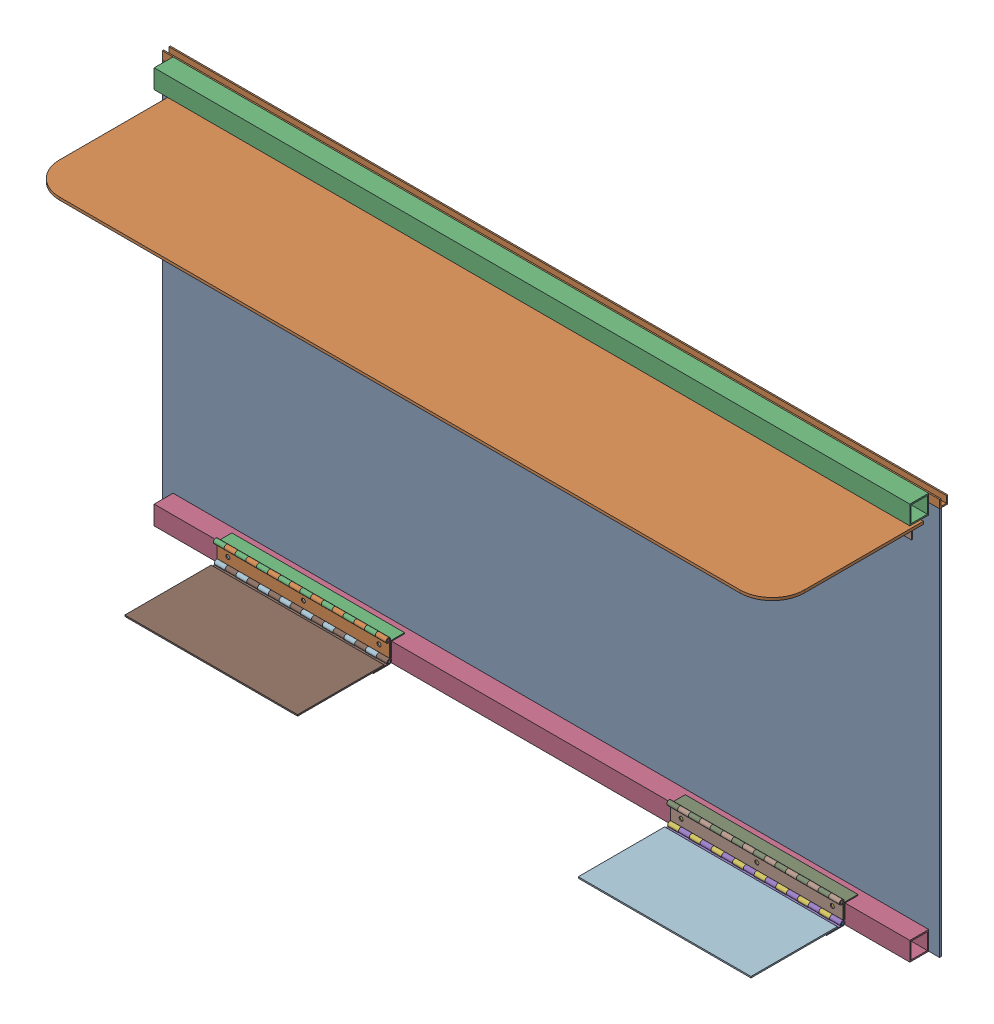
SolidWorks assembly FE-00004_ASM, configuration Default. Lengths in mm.
Overall size (1828.8 933.45 374.65).
43 component instances, 17 part files, 0 mates.
Components (placement in the parent):
- FE-00004-01-1: FE-00004-01 [Default] at origin size (1828.8 914.4 4.76)
- FE-00004-05-1: FE-00004-05 [Default] at (0 914.4 -4.7625) x (1 0 0) z (0 -1 0) size (1828.8 19.05 19.05)
- FE-00004-04-1: FE-00004-04 [Default] at (0 911.225 26.9875) size (1778 44.45 44.45)
- FE-00004-04-2: FE-00004-04 [Default] at (0 22.225 26.9875) size (1778 44.45 44.45)
- FE-00004-02_ASM-1: FE-00004-02_ASM [Default] at (-647.7 858.139 4.7625) x (-1 0 0) z (0 0 -1) size (406.4 43.56 43.56)
  - FE-00004-02-A-1: FE-00004-02-A [Default] at origin size (406.4 43.56 10.92)
  - FE-00004-02-A-2: FE-00004-02-A [Default] at (0 5.461 -5.461) x (-1 0 0) z (0 1 0) size (406.4 43.56 10.92)
  - FE-00004-02-B-1: FE-00004-02-B [Default] at (0 0 -5.461) size (406.4 6.35 6.35)
- FE-00004-02_ASM-2: FE-00004-02_ASM [Default] at (647.7 858.139 4.7625) x (-1 0 0) z (0 0 -1) size (406.4 43.56 43.56)
  - FE-00004-02-A-1: FE-00004-02-A [Default] at origin size (406.4 43.56 10.92)
  - FE-00004-02-A-2: FE-00004-02-A [Default] at (0 5.461 -5.461) x (-1 0 0) z (0 1 0) size (406.4 43.56 10.92)
  - FE-00004-02-B-1: FE-00004-02-B [Default] at (0 0 -5.461) size (406.4 6.35 6.35)
- FE-00004-03_ASM-1: FE-00004-03_ASM [Default] at (0 863.6 10.2235) x (1 0 0) z (0 1 0) size (482.6 43.56 43.56)
  - FE-00004-03-A-1: FE-00004-03-A [Default] at origin size (482.6 43.56 10.92)
  - FE-00004-03-B-1: FE-00004-03-B [Default] at (0 5.461 -5.461) x (-1 0 0) z (0 1 0) size (482.6 43.56 10.92)
  - FE-00004-03-C-1: FE-00004-03-C [Default] at (0 0 -5.461) size (482.6 6.35 6.35)
- FE-00004-06-1: FE-00004-06 [Default] at (127 863.6 182.5625) size (1752.6 6.35 355.6)
- FE-00004-09-1: FE-00004-09 [Default] at (-403.9235 787.4 155.2839) x (1 0 0) z (0 -1 0) size (3.18 302.13 152.4)
- FE-00004-08_ASM-1: FE-00004-08_ASM [Default] at (-400.7485 858.139 179.8901) x (0 0 1) z (-1 0 0) size (203.2 43.56 43.56)
  - FE-00004-08-A-1: FE-00004-08-A [Default] at origin size (203.2 43.56 10.92)
  - FE-00004-08-A-2: FE-00004-08-A [Default] at (0 5.461 -5.461) x (-1 0 0) z (0 1 0) size (203.2 43.56 10.92)
  - FE-00004-08-C-1: FE-00004-08-C [Default] at (0 0 -5.461) size (203.2 6.35 6.35)
- FE-00004-09-2: FE-00004-09 [Default] at (400.7485 787.4 155.2839) x (1 0 0) z (0 -1 0) size (3.18 302.13 152.4)
- FE-00004-08_ASM-2: FE-00004-08_ASM [Default] at (400.7485 858.139 179.8901) x (0 0 -1) z (1 0 0) size (203.2 43.56 43.56)
  - FE-00004-08-A-1: FE-00004-08-A [Default] at origin size (203.2 43.56 10.92)
  - FE-00004-08-A-2: FE-00004-08-A [Default] at (0 5.461 -5.461) x (-1 0 0) z (0 1 0) size (203.2 43.56 10.92)
  - FE-00004-08-C-1: FE-00004-08-C [Default] at (0 0 -5.461) size (203.2 6.35 6.35)
- FE-00004-07_ASM-1: FE-00004-07_ASM [Default] at (-533.4 0 54.6735) x (-1 0 0) z (0 -1 0) size (406.4 73.91 55.37)
  - FE-00004-07-A_1-1: FE-00004-07-A_1 [Default] at origin size (406.4 43.56 10.92)
  - FE-00004-07-A_AF2-1: FE-00004-07-A_AF2 [Default] at (0 5.461 -5.461) x (-1 0 0) z (0 1 0) size (406.4 43.56 10.92)
  - FE-00004-07-B_1-1: FE-00004-07-B_1 [Default] at (0 0 -5.461) size (406.4 6.35 6.35)
  - FE-00004-07-A_AF3-1: FE-00004-07-A_AF3 [Default] at (0 3.175 -49.911) x (1 0 0) z (0 1 0) size (406.4 43.56 10.92)
  - FE-00004-07-A_1-2: FE-00004-07-A_1 [Default] at (0 -2.286 -44.45) x (-1 0 0) z (0 0 1) size (406.4 43.56 10.92)
  - FE-00004-07-B_1-2: FE-00004-07-B_1 [Default] at (0 -2.286 -49.911) size (406.4 6.35 6.35)
- FE-00004-07_ASM-2: FE-00004-07_ASM [Default] at (533.4 0 54.6735) x (-1 0 0) z (0 -1 0) size (406.4 73.91 55.37)
  - FE-00004-07-A_1-1: FE-00004-07-A_1 [Default] at origin size (406.4 43.56 10.92)
  - FE-00004-07-A_AF2-1: FE-00004-07-A_AF2 [Default] at (0 5.461 -5.461) x (-1 0 0) z (0 1 0) size (406.4 43.56 10.92)
  - FE-00004-07-B_1-1: FE-00004-07-B_1 [Default] at (0 0 -5.461) size (406.4 6.35 6.35)
  - FE-00004-07-A_AF3-1: FE-00004-07-A_AF3 [Default] at (0 3.175 -49.911) x (1 0 0) z (0 1 0) size (406.4 43.56 10.92)
  - FE-00004-07-A_1-2: FE-00004-07-A_1 [Default] at (0 -2.286 -44.45) x (-1 0 0) z (0 0 1) size (406.4 43.56 10.92)
  - FE-00004-07-B_1-2: FE-00004-07-B_1 [Default] at (0 -2.286 -49.911) size (406.4 6.35 6.35)
- FE-00004-10-1: FE-00004-10 [Default] at (-533.4 2.286 168.9735) size (406.4 3.17 203.2)
- FE-00004-10-2: FE-00004-10 [Default] at (533.4 2.286 168.9735) size (406.4 3.17 203.2)
